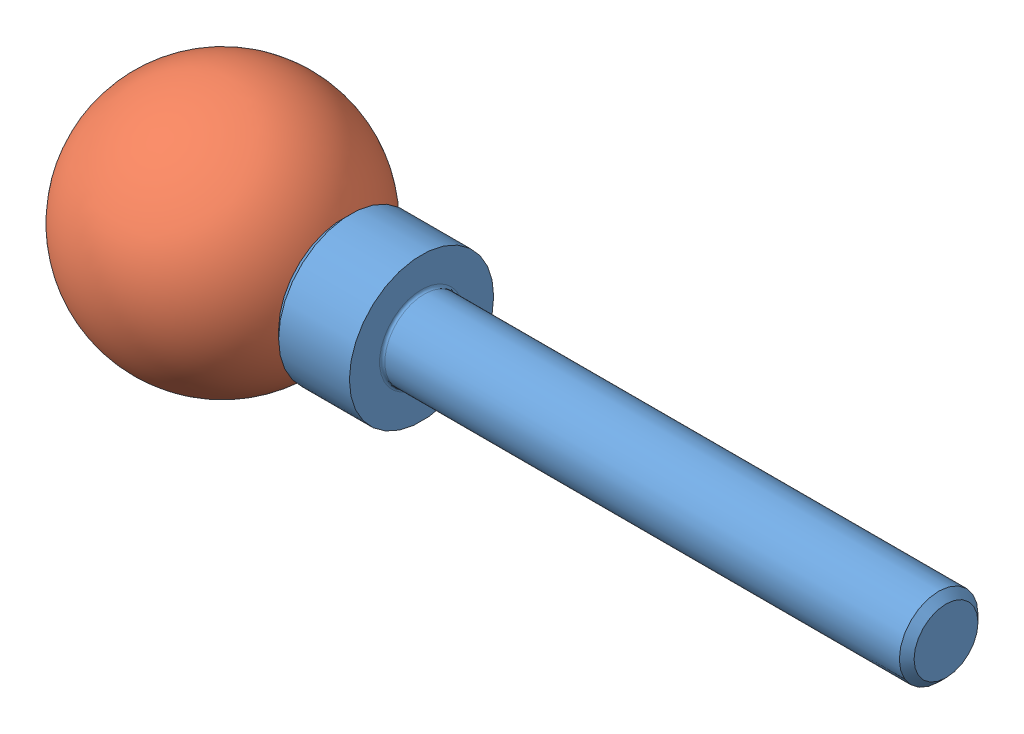
SolidWorks assembly Assem-ball on nut-20, configuration Default. Lengths in mm.
Overall size (32.35 12.89 12.89).
2 component instances, 2 part files, 2 mates.
Components (placement in the parent):
- socket head cap screw_am-1: socket head cap screw_am [B18.3.1M - 3 x 0.5 x 20 Hex SHCS -- 20NHX] at (-20.2329 3.4218 -0.8826) size (23 5.5 5.5)
- Part-ebay-3-8 sling shot ammo-1: Part-ebay-3-8 sling shot ammo [Default] at (-24.8202 3.4218 -0.8826) x (1 0 0) z (0 -0.472388 -0.881391) size (9.53 9.53 9.53)
Mates (geometry in assembly coordinates):
- Coincident1: coincident aligned: line of Part-ebay-3-8 sling shot ammo-1 through (-19.5814 3.4218 -0.8826) axis (-1 0 0)
- Coincident3: coincident: point of socket head cap screw_am-1; unknown of Part-ebay-3-8 sling shot ammo-1
